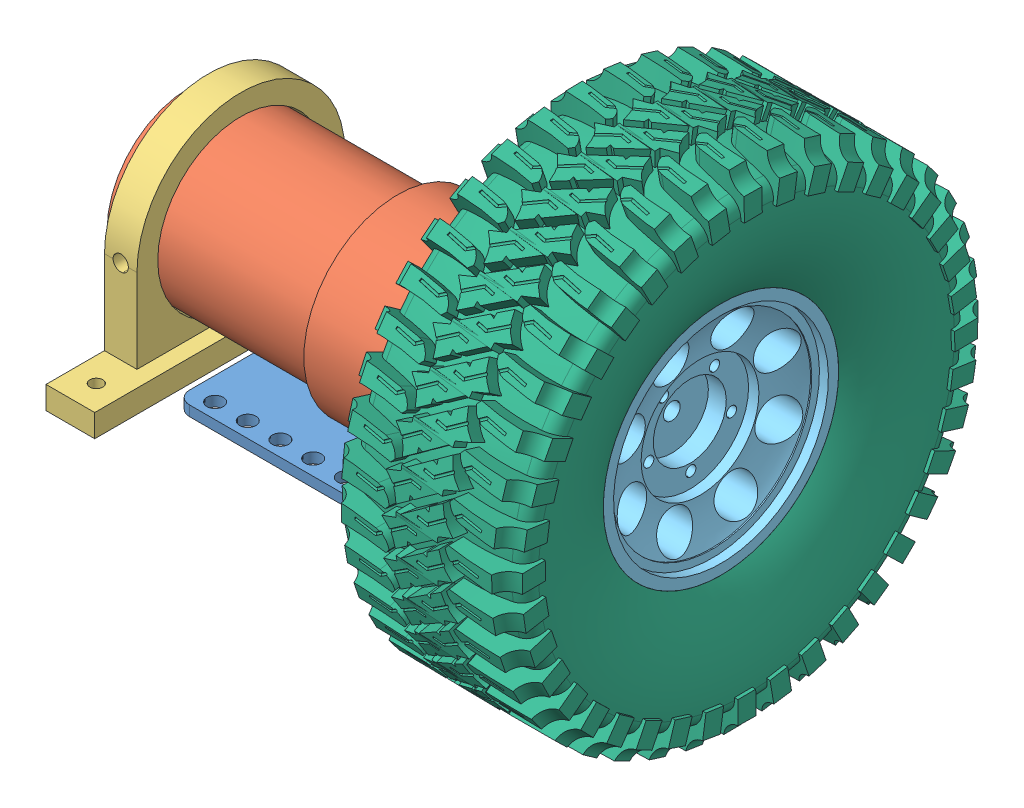
SolidWorks assembly MotorAssembly, configuration Default. Lengths in mm.
Overall size (109.89 110.17 110.17).
6 component instances, 6 part files, 13 mates.
Components (placement in the parent):
- FrontMotorSupport-1: FrontMotorSupport [Default] at (25.1496 -16.5734 -2.9307) size (51.5 39.6 37.5)
- Motor-1: Motor [Default] at (25.1496 4.2766 -2.9307) x (0 0 -1) z (1 0 0) size (36.8 36.8 85.85)
- BackMotorSupport-1: BackMotorSupport [Default] at (-33.7154 -16.5734 -2.9307) size (9.52 41.17 63.5)
- MotorShaftMount-1: MotorShaftMount [Default] at (51.2964 12.7766 -2.9307) x (0 0.854074 0.520152) z (-1 0 0) size (13.86 12 18.15)
- Rim-1: Rim [Default] at (45.1484 12.7766 -2.9307) x (1 0 0) z (0 0.023428 -0.999726) size (24 46 46)
- Tire-1: Tire [Default] at (51.2984 12.7766 -2.9307) x (1 0 0) z (0 -0.169329 0.98556) size (35.57 95.4 95.4)
Mates (geometry in assembly coordinates):
- Concentric1: concentric anti-aligned: cylinder of FrontMotorSupport-1 through (27.1496 17.8299 -10.7557) axis (-1 0 0) radius 1.675; cylinder of Motor-1 through (15.1496 17.8299 -10.7557) axis (1 0 0) radius 1.675
- Concentric2: concentric anti-aligned: cylinder of FrontMotorSupport-1 through (27.1496 17.8299 4.8943) axis (-1 0 0) radius 1.675; cylinder of Motor-1 through (15.1496 17.8299 4.8943) axis (1 0 0) radius 1.675
- Coincident1: coincident anti-aligned: plane of FrontMotorSupport-1 through (25.1496 -16.5734 -2.9307) normal (-1 0 0); plane of Motor-1 through (25.1496 4.2766 -2.9307) normal (1 0 0)
- Concentric3: concentric anti-aligned: cylinder of Motor-1 through (-40.7004 4.2766 -2.9307) axis (1 0 0) radius 16; cylinder of BackMotorSupport-1 through (-30.5404 4.2766 -2.9307) axis (-1 0 0) radius 16.256
- Parallel1: parallel aligned: plane of FrontMotorSupport-1 through (27.1496 -16.5734 -2.9307) normal (0 -1 0); plane of BackMotorSupport-1 through (-30.5404 -16.5734 -2.9307) normal (0 -1 0)
- Distance1: distance = 3.81 mm aligned: plane of BackMotorSupport-1 through (-36.8904 -16.5734 -2.9307) normal (-1 0 0); plane of Motor-1 through (-40.7004 4.2766 -2.9307) normal (-1 0 0)
- Concentric4: concentric anti-aligned: cylinder of Motor-1 through (45.1496 12.7766 -2.9307) axis (-1 0 0) radius 3; cylinder of MotorShaftMount-1 through (33.1496 12.7766 -2.9307) axis (1 0 0) radius 3
- Coincident2: coincident anti-aligned: plane of Motor-1 through (33.1496 12.7766 -2.9307) normal (1 0 0); plane of MotorShaftMount-1 through (33.1496 12.7766 -2.9307) normal (-1 0 0)
- Coincident3: coincident anti-aligned: plane of MotorShaftMount-1 through (51.2964 12.7766 -2.9307) normal (1 0 0); plane of Rim-1 through (51.2964 12.7766 -2.9307) normal (-1 0 0)
- Coincident4: coincident anti-aligned: plane of MotorShaftMount-1 through (45.1496 18.6938 0.673) normal (0 0.999726 0.023428); plane of Rim-1 through (51.2964 18.6938 0.673) normal (0 -0.999726 -0.023428)
- Coincident5: coincident anti-aligned: plane of MotorShaftMount-1 through (45.1496 6.6971 0.3919) normal (0 -0.520152 0.854074); plane of Rim-1 through (51.2964 6.6971 0.3919) normal (0 0.520152 -0.854074)
- Concentric5: concentric anti-aligned: cylinder of Rim-1 through (45.1484 12.7766 -2.9307) axis (-1 0 0) radius 23; cylinder of Tire-1 through (63.2984 12.7766 -2.9307) axis (1 0 0) radius 23
- Coincident9: coincident anti-aligned: circle of Rim-1; circle of Tire-1
